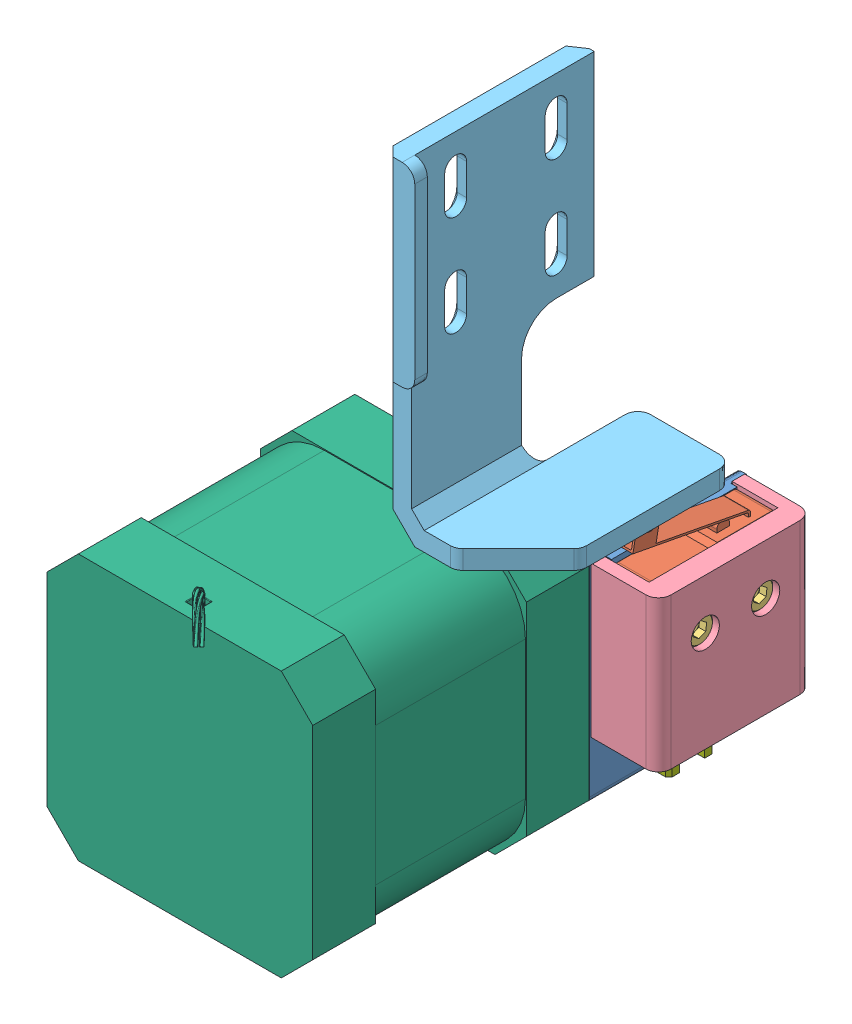
SolidWorks assembly TML Aufero_Laser_2 X_Axis Limit Switch Assem1, configuration Default. Lengths in mm.
Overall size (52.99 101.39 77.9).
8 component instances, 7 part files, 4 mates.
Components (placement in the parent):
- TML Aufero_Laser_2 X_Axis Limit Switch Stepper Mount V1-1: TML Aufero_Laser_2 X_Axis Limit Switch Stepper Mount V1 [Default] at (10.3672 9.352 -24.3242) size (12 32.99 25)
- Microswitch 20mm-1: Microswitch 20mm [Default] at (35.5388 15.7329 -21.8646) x (-1 0 0) z (0 0 -1) size (6.4 23.41 21.8)
- socket head cap screw_am-1: socket head cap screw_am [B18.3.1M - 2.5 x 0.45 x 10 Hex SHCS -- 10NHX] at (41.2388 18.0329 -7.0146) x (-1 0 0) z (0 0.924225 0.381849) size (12.5 4.5 4.5)
- socket head cap screw_am-2: socket head cap screw_am [B18.3.1M - 2.5 x 0.45 x 10 Hex SHCS -- 10NHX] at (41.2388 18.0329 -16.6146) x (-1 0 0) z (0 0.924225 0.381849) size (12.5 4.5 4.5)
- TML Aufero_Laser_2 X_Axis Limit Switch Cap Short v1-1: TML Aufero_Laser_2 X_Axis Limit Switch Cap Short v1 [Default] at (38.6076 12.9794 -11.8167) x (0 0 -1) z (1 0 0) size (24.5 26 10.8)
- TML Aufero_Laser_2 X_Axis Limit Switch (Z)Carriage Rear Mount V1 -1: TML Aufero_Laser_2 X_Axis Limit Switch (Z)Carriage Rear Mount V1  [Default] at (22.0105 74.3888 -16.2915) x (0 1 0) z (1 0 0) size (53.5 35.5 20)
- Nema 17 Stepper Motor-1: Nema 17 Stepper Motor [Default] at (10.2666 9.6508 44.7686) x (0 0 -1) z (1 0 0) size (77.9 47.49 42.3)
- Cable Guide-1: Cable Guide [Default] at (87.9451 7.8855 11.3482) x (0 0 1) z (0 -1 0) size (7.4 3.8 14)
Mates (geometry in assembly coordinates):
- Concentric1: concentric anti-aligned: cylinder of Microswitch 20mm-1 through (35.5388 18.0329 -7.0146) axis (-1 0 0) radius 1.2; cylinder of socket head cap screw_am-1 through (72.9888 18.0329 -7.0146) axis (1 0 0) radius 2.25
- Coincident1: coincident anti-aligned: plane of Microswitch 20mm-1 through (38.7388 17.7934 -7.0146) normal (1 0 0); plane of socket head cap screw_am-1 through (38.7388 17.1738 -4.9351) normal (-1 0 0)
- Concentric2: concentric anti-aligned: cylinder of Microswitch 20mm-1 through (35.5388 18.0329 -16.6146) axis (-1 0 0) radius 1.2; cylinder of socket head cap screw_am-2 through (72.9888 18.0329 -16.6146) axis (1 0 0) radius 2.25
- Coincident2: coincident anti-aligned: plane of Microswitch 20mm-1 through (38.7388 17.7934 -16.6146) normal (1 0 0); plane of socket head cap screw_am-2 through (38.7388 17.1738 -14.5351) normal (-1 0 0)
